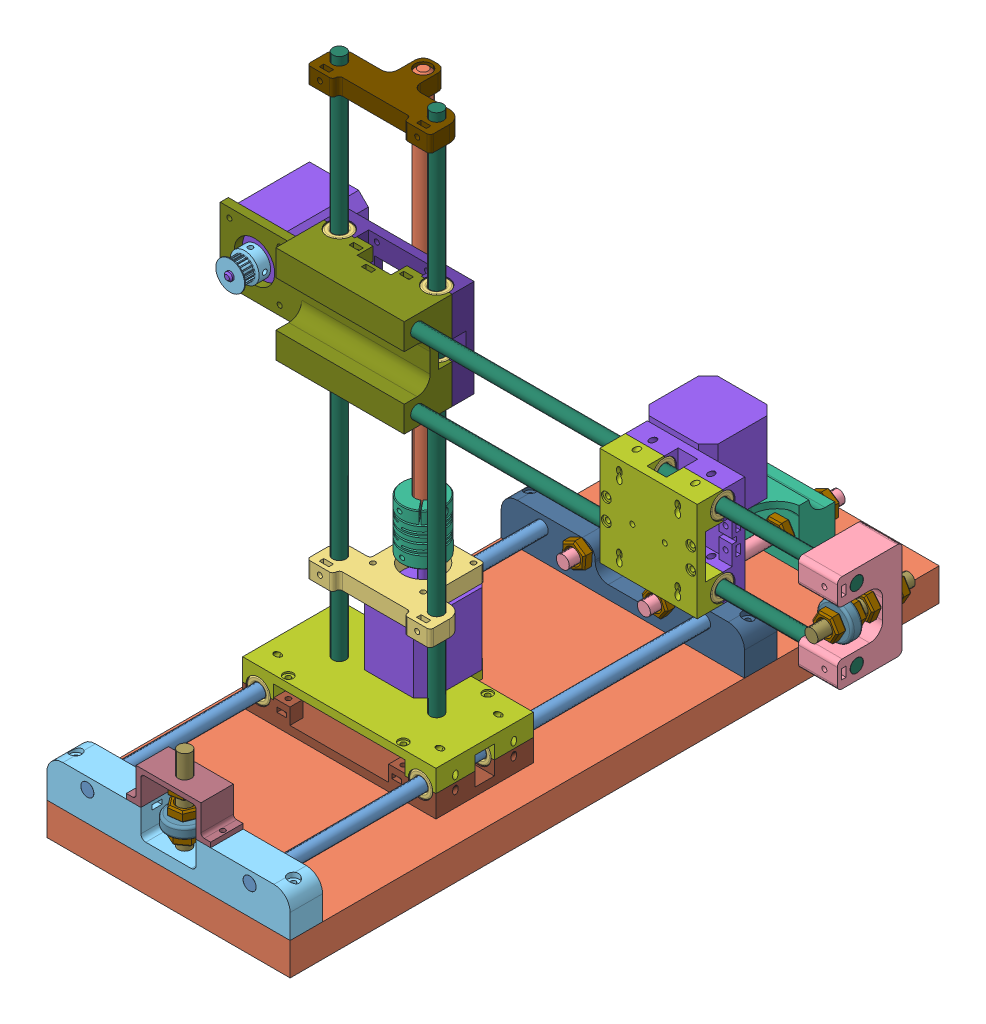
SolidWorks assembly Cartesian assembly, configuration Default. Lengths in mm.
Overall size (405.4 374.45 403.92).
61 component instances, 26 part files, 139 mates.
Components (placement in the parent):
- 8x300mm round stock-1: 8x300mm round stock [Default] at (139.3217 164.8041 244.399) size (8 8 300)
- 8x300mm round stock-2: 8x300mm round stock [Default] at (39.3217 164.8041 244.399) size (8 8 300)
- Wooden base-1: Wooden base [Default] at (89.3217 126.8041 344.399) size (150 20 400)
- LM8uu-1: LM8uu [Default] at (139.3217 164.8041 439.115) x (0.366994 -0.930223 0) z (0.930223 0.366994 0) size (15 24 15)
- LM8uu-2: LM8uu [Default] at (139.3217 164.8041 403.115) x (0.340465 -0.940257 0) z (0.940257 0.340465 0) size (15 24 15)
- LM8uu-3: LM8uu [Default] at (39.3217 164.8041 403.115) x (0.999761 -0.021839 0) z (0.021839 0.999761 0) size (15 24 15)
- LM8uu-4: LM8uu [Default] at (39.3217 164.8041 439.115) x (0.974096 0.226136 0) z (-0.226136 0.974096 0) size (15 24 15)
- 8mm threaded rod-1: 8mm threaded rod [Default] at (114.3217 164.8041 276.399) x (1 0 0) z (0 1 0) size (8 120 8)
- 8mm threaded rod-2: 8mm threaded rod [Default] at (64.3217 164.8041 156.399) x (1 0 0) z (0 -1 0) size (8 120 8)
- Base screw bracket with idler-5: Base screw bracket with idler [Default] at (89.3217 159.3041 524.399) x (1 0 0) z (0 -1 0) size (150 20 25)
- Stepper mount-1: Stepper mount [Default] at (89.0007 181.8041 211.549) x (1 0 0) z (0 0 -1) size (71.23 35 64.3)
- Main carriage-1: Main carriage [Default] at (89.3217 178.3541 409.115) x (1 0 0) z (0 0 -1) size (119.1 13.55 73.05)
- Nema 17 48mm-1: Nema 17 48mm [Default] at (89.0007 225.8041 211.549) x (-1 0 0) z (0 0 1) size (42.3 66 42.3)
- 8mm nut-1: 8mm nut [Default] at (114.3217 164.8041 162.399) x (1 0 0) z (0 -1 0) size (14.4 6 16.14)
- 8mm nut-2: 8mm nut [Default] at (114.3217 164.8041 264.399) x (0.844183 -0.536054 0) z (-0.536054 -0.844183 0) size (14.4 6 16.14)
- 8mm nut-3: 8mm nut [Default] at (64.3217 164.8041 168.399) x (0.023312 -0.999728 0) z (0.999728 0.023312 0) size (14.4 6 16.14)
- 8mm nut-4: 8mm nut [Default] at (64.3217 164.8041 270.399) x (0.389435 -0.921054 0) z (0.921054 0.389435 0) size (14.4 6 16.14)
- 8mm nut-5: 8mm nut [Default] at (114.3217 164.8041 190.399) x (0.898687 -0.438591 0) z (-0.438591 -0.898687 0) size (14.4 6 16.14)
- 8mm nut-6: 8mm nut [Default] at (114.3217 164.8041 238.399) x (0.371735 -0.928339 0) z (-0.928339 -0.371735 0) size (14.4 6 16.14)
- 8mm nut-7: 8mm nut [Default] at (64.3217 164.8041 196.399) x (1 0 0) z (0 1 0) size (14.4 6 16.14)
- 8mm nut-8: 8mm nut [Default] at (64.3217 164.8041 244.399) x (0.8519 -0.523705 0) z (0.523705 0.8519 0) size (14.4 6 16.14)
- Base screw bracket with out idler-1: Base screw bracket with out idler [Default] at (89.3217 159.3041 244.399) x (1 0 0) z (0 -1 0) size (150 20 25)
- Main carriage with set screw-1: Main carriage with set screw [Default] at (89.3217 151.2541 409.115) size (119.1 14.8 60)
- 8mm threaded rod for idler-1: 8mm threaded rod for idler [Default] at (89.3217 146.8041 534.399) x (0.152757 0 0.988264) z (-0.988264 0 0.152757) size (8 60 8)
- Idler bracket-1: Idler bracket [Default] at (89.3217 180.6682 524.399) size (52 21 20)
- 8mm ball bearing-1: 8mm ball bearing [Default] at (89.3217 168.8541 534.399) x (0.948507 0 0.316755) z (-0.316755 0 0.948507) size (22 7 22)
- 8mmx350mm-1: 8mmx350mm [Default] at (59.3217 151.2541 409.115) x (0 1 0) z (0.685543 0 0.728032) size (350 8 8)
- 8mmx350mm-2: 8mmx350mm [Default] at (119.3217 151.2541 409.115) x (0 1 0) z (0.348511 0 -0.937305) size (350 8 8)
- LM8uu-5: LM8uu [Default] at (119.3217 370.4443 409.115) x (0.524592 0 0.851354) z (0.851354 0 -0.524592) size (15 24 15)
- LM8uu-6: LM8uu [Default] at (59.3217 406.4443 409.115) x (0.379199 0 0.925315) z (0.925315 0 -0.379199) size (15 24 15)
- LM8uu-7: LM8uu [Default] at (119.3217 406.4443 409.115) x (0.235232 0 0.971939) z (0.971939 0 -0.235232) size (15 24 15)
- LM8uu-8: LM8uu [Default] at (59.3217 370.4443 409.115) x (-0.852729 0 -0.522354) z (-0.522354 0 0.852729) size (15 24 15)
- z carriage with set screw-1: z carriage with set screw [Default] at (89.3217 376.4443 422.665) x (1 0 0) z (0 1 0) size (129.4 30.8 60)
- z carriage-2: z carriage [Default] at (89.3217 376.4443 395.565) x (-1 0 0) z (0 1 0) size (79.1 31.2 60)
- 8mmx350mm-3: 8mmx350mm [Default] at (49.7717 398.4443 430.665) x (1 0 0) z (0 -0.803458 -0.595361) size (350 8 8)
- 8mmx350mm-4: 8mmx350mm [Default] at (49.7717 354.4443 430.665) x (1 0 0) z (0 -0.831172 -0.556016) size (350 8 8)
- Top spacer-1: Top spacer [Default] at (89.3217 486.2541 409.115) x (1 0 0) z (0 0 1) size (76 10 40.7)
- Lift nut-1: Lift nut [Default] at (89.3217 364.8673 387.412) x (0.5 0 -0.866025) z (0.866025 0 0.5) size (30 25.25 30)
- Lift rod-1: Lift rod [Default] at (89.3217 246.3541 387.412) x (-0.592349 0 0.805681) z (-0.805681 0 -0.592349) size (10 250 10)
- Nema 17 48mm-2: Nema 17 48mm [Default] at (89.3217 178.3541 387.412) size (42.3 66 42.3)
- Stepper brace-1: Stepper brace [Default] at (89.3217 222.3541 409.115) x (1 0 0) z (0 0 1) size (76 10 52.7)
- Nema 17 48mm-3: Nema 17 48mm [Default] at (20.6217 376.4443 373.665) x (1 0 0) z (0 -1 0) size (42.3 66 42.3)
- X belt idler-1: X belt idler [Default] at (375.7717 376.4443 430.665) x (0 -1 0) z (0 0 1) size (60 24 40)
- 8mm ball bearing-2: 8mm ball bearing [Default] at (391.7717 376.4443 433.165) x (0.976827 -0.214031 0) z (-0.214031 -0.976827 0) size (22 7 22)
- 8mm threaded rod for idler-2: 8mm threaded rod for idler [Default] at (391.7717 376.4443 390.665) x (0.112676 -0.993632 0) z (-0.993632 -0.112676 0) size (8 60 8)
- 8mm nut-9: 8mm nut [Default] at (391.7717 376.4443 396.665) x (0.894515 -0.447039 0) z (-0.447039 -0.894515 0) size (14.4 6 16.14)
- 8mm nut-10: 8mm nut [Default] at (391.7717 376.4443 423.665) x (0.798629 0.601824 0) z (0.601824 -0.798629 0) size (14.4 6 16.14)
- 8mm nut-11: 8mm nut [Default] at (391.7717 376.4443 436.665) x (0.898687 -0.438591 0) z (-0.438591 -0.898687 0) size (14.4 6 16.14)
- 8mm nut-12: 8mm nut [Default] at (391.7717 376.4443 414.665) x (0.749973 0.661469 0) z (0.661469 -0.749973 0) size (14.4 6 16.14)
- GT2-Pulley-20-Teeth-5mm-Bore-1: GT2-Pulley-20-Teeth-5mm-Bore [Default] at (20.6217 376.4443 421.665) size (17.8 17.8 16)
- GT2-Pulley-20-Teeth-5mm-Bore-2: GT2-Pulley-20-Teeth-5mm-Bore [Default] at (89.0007 179.8041 211.549) x (0.98894 0 -0.148316) z (0 -1 0) size (17.8 17.8 16)
- 8mm nut-13: 8mm nut [Default] at (89.3217 189.8041 534.399) x (0.78051 0 -0.625144) z (-0.625144 0 -0.78051) size (14.4 6 16.14)
- 8mm nut-14: 8mm nut [Default] at (89.3217 165.3541 534.399) x (0.998165 0 -0.060557) z (-0.060557 0 -0.998165) size (14.4 6 16.14)
- 8mm nut-15: 8mm nut [Default] at (89.3217 178.3541 534.399) x (0.822996 0 -0.568047) z (-0.568047 0 -0.822996) size (14.4 6 16.14)
- SRB-26C-6,35-10-1: SRB-26C-6,35-10 [По умолчанию] at (89.3217 253.6541 387.412) x (0.780592 0 -0.625041) z (0 1 0) size (26.2 26.2 31.4)
- LM8uu-9: LM8uu [Default] at (281.1911 398.4443 430.665) x (0 0.86871 -0.495321) z (0 0.495321 0.86871) size (15 24 15)
- LM8uu-10: LM8uu [Default] at (317.1911 398.4443 430.665) x (0 0.486453 -0.873707) z (0 0.873707 0.486453) size (15 24 15)
- LM8uu-11: LM8uu [Default] at (281.1911 354.4443 430.665) x (0 0.81715 -0.576426) z (0 0.576426 0.81715) size (15 24 15)
- LM8uu-12: LM8uu [Default] at (317.1911 354.4443 430.665) x (0 0.462218 0.886767) z (0 -0.886767 0.462218) size (15 24 15)
- x carriage-1: x carriage [Default] at (287.1911 376.4443 446.415) x (0 -1 0) z (1 0 0) size (61.1 15.75 60)
- x carriage with nut holders-1: x carriage with nut holders [Default] at (287.1911 376.4443 417.115) x (0 1 0) z (1 0 0) size (61.1 13.55 60)
Mates (geometry in assembly coordinates):
- Coincident1: coincident aligned: plane of 8x300mm round stock-1 through (139.3217 164.8041 544.399) normal (0 0 1); plane of 8x300mm round stock-2 through (39.3217 164.8041 544.399) normal (0 0 1)
- Concentric1: concentric anti-aligned: cylinder of 8x300mm round stock-2 through (39.3217 164.8041 544.399) axis (0 0 -1) radius 4; cylinder of LM8uu-3 through (39.3217 164.8041 379.115) axis (0 0 1) radius 4
- Concentric2: concentric anti-aligned: cylinder of 8x300mm round stock-2 through (39.3217 164.8041 544.399) axis (0 0 -1) radius 4; cylinder of LM8uu-4 through (39.3217 164.8041 415.115) axis (0 0 1) radius 4
- Concentric3: concentric anti-aligned: cylinder of 8x300mm round stock-1 through (139.3217 164.8041 544.399) axis (0 0 -1) radius 4; cylinder of LM8uu-1 through (139.3217 164.8041 415.115) axis (0 0 1) radius 4
- Concentric5: concentric anti-aligned: cylinder of 8x300mm round stock-1 through (139.3217 164.8041 544.399) axis (0 0 -1) radius 4; cylinder of LM8uu-2 through (139.3217 164.8041 379.115) axis (0 0 1) radius 4
- Coincident2: coincident aligned: plane of 8x300mm round stock-1 through (139.3217 164.8041 544.399) normal (0 0 1); plane of Wooden base-1 through (14.3217 146.8041 544.399) normal (0 0 1)
- Coincident3: coincident aligned: plane of LM8uu-1 through (139.3217 164.8041 439.115) normal (0 0 1); plane of LM8uu-4 through (39.3217 164.8041 439.115) normal (0 0 1)
- Coincident4: coincident aligned: plane of LM8uu-2 through (139.3217 164.8041 403.115) normal (0 0 1); plane of LM8uu-3 through (39.3217 164.8041 403.115) normal (0 0 1)
- Coincident5: coincident aligned: plane of 8x300mm round stock-1 through (139.3217 164.8041 244.399) normal (0 1 0); plane of 8x300mm round stock-2 through (39.3217 164.8041 244.399) normal (0 1 0)
- Coincident12: coincident anti-aligned: plane of 8mm threaded rod-1 through (114.3217 164.8041 276.399) normal (0 1 0); plane of 8mm threaded rod-2 through (64.3217 164.8041 156.399) normal (0 -1 0)
- Coincident13: coincident aligned: plane of 8x300mm round stock-1 through (139.3217 164.8041 244.399) normal (0 1 0); plane of 8mm threaded rod-1 through (114.3217 164.8041 276.399) normal (0 1 0)
- Concentric6: concentric aligned: cylinder of 8x300mm round stock-1 through (139.3217 164.8041 544.399) axis (0 0 -1) radius 4; cylinder of Base screw bracket with idler-5 through (139.3217 164.8041 544.399) axis (0 0 -1) radius 4.05
- Concentric12: concentric aligned: cylinder of 8x300mm round stock-2 through (39.3217 164.8041 544.399) axis (0 0 -1) radius 4; cylinder of Base screw bracket with idler-5 through (39.3217 164.8041 544.399) axis (0 0 -1) radius 4.05
- Coincident18: coincident aligned: plane of Wooden base-1 through (14.3217 146.8041 544.399) normal (0 0 1); plane of Base screw bracket with idler-5 through (89.3217 159.3041 544.399) normal (0 0 1)
- Coincident19: coincident anti-aligned: plane of Wooden base-1 through (89.3217 146.8041 344.399) normal (0 1 0); plane of Base screw bracket with idler-5 through (14.3217 146.8041 544.399) normal (0 -1 0)
- Coincident20: coincident aligned: plane of Wooden base-1 through (164.3217 146.8041 144.399) normal (1 0 0); plane of Base screw bracket with idler-5 through (164.3217 171.8041 544.399) normal (1 0 0)
- Coincident22: coincident anti-aligned: plane of Wooden base-1 through (89.3217 146.8041 344.399) normal (0 1 0); plane of Stepper mount-1 through (89.0007 146.8041 184.399) normal (0 -1 0)
- Concentric14: concentric anti-aligned: cylinder of 8mm threaded rod-2 through (64.3217 164.8041 276.399) axis (0 0 -1) radius 4; cylinder of Stepper mount-1 through (64.3217 164.8041 168.399) axis (0 0 1) radius 4.05
- Concentric15: concentric anti-aligned: cylinder of LM8uu-2 through (139.3217 164.8041 379.115) axis (0 0 1) radius 7.5; cylinder of Main carriage-1 through (139.3217 164.8041 403.115) axis (0 0 -1) radius 7.55
- Concentric16: concentric aligned: cylinder of LM8uu-4 through (39.3217 164.8041 415.115) axis (0 0 1) radius 7.5; cylinder of Main carriage-1 through (39.3217 164.8041 415.115) axis (0 0 1) radius 7.55
- Coincident23: coincident aligned: plane of LM8uu-4 through (39.3217 164.8041 439.115) normal (0 0 1); plane of Main carriage-1 through (29.7717 173.3541 439.115) normal (0 0 1)
- Coincident24: coincident aligned: plane of LM8uu-1 through (139.3217 164.8041 439.115) normal (0 0 1); plane of Main carriage-1 through (29.7717 173.3541 439.115) normal (0 0 1)
- Coincident25: coincident aligned: plane of LM8uu-2 through (139.3217 164.8041 379.115) normal (0 0 -1); plane of Main carriage-1 through (29.7717 173.3541 379.115) normal (0 0 -1)
- Coincident26: coincident aligned: plane of LM8uu-3 through (39.3217 164.8041 379.115) normal (0 0 -1); plane of Main carriage-1 through (29.7717 173.3541 379.115) normal (0 0 -1)
- Coincident27: coincident anti-aligned: plane of Stepper mount-1 through (89.0007 181.8041 211.549) normal (0 1 0); plane of Nema 17 48mm-1 through (89.0007 181.8041 211.549) normal (0 -1 0)
- Coincident28: coincident aligned: plane of Stepper mount-1 through (110.1507 177.8041 232.699) normal (1 0 0); plane of Nema 17 48mm-1 through (110.1507 181.8041 211.549) normal (1 0 0)
- Coincident29: coincident aligned: plane of Stepper mount-1 through (67.8507 177.8041 232.699) normal (0 0 1); plane of Nema 17 48mm-1 through (89.0007 181.8041 232.699) normal (0 0 1)
- Concentric21: concentric anti-aligned: cylinder of 8mm threaded rod-1 through (114.3217 164.8041 156.399) axis (0 0 1) radius 4; cylinder of 8mm nut-2 through (114.3217 164.8041 270.399) axis (0 0 -1) radius 4
- Concentric22: concentric anti-aligned: cylinder of 8mm threaded rod-2 through (64.3217 164.8041 276.399) axis (0 0 -1) radius 4; cylinder of 8mm nut-3 through (64.3217 164.8041 162.399) axis (0 0 1) radius 4
- Concentric23: concentric anti-aligned: cylinder of 8mm threaded rod-1 through (114.3217 164.8041 156.399) axis (0 0 1) radius 4; cylinder of 8mm nut-1 through (114.3217 164.8041 168.399) axis (0 0 -1) radius 4
- Concentric24: concentric anti-aligned: cylinder of 8mm threaded rod-2 through (64.3217 164.8041 276.399) axis (0 0 -1) radius 4; cylinder of 8mm nut-4 through (64.3217 164.8041 264.399) axis (0 0 1) radius 4
- Concentric25: concentric anti-aligned: cylinder of 8mm threaded rod-1 through (114.3217 164.8041 156.399) axis (0 0 1) radius 4; cylinder of 8mm nut-5 through (114.3217 164.8041 196.399) axis (0 0 -1) radius 4
- Concentric26: concentric anti-aligned: cylinder of 8mm threaded rod-1 through (114.3217 164.8041 156.399) axis (0 0 1) radius 4; cylinder of 8mm nut-6 through (114.3217 164.8041 244.399) axis (0 0 -1) radius 4
- Concentric27: concentric anti-aligned: cylinder of 8mm threaded rod-2 through (64.3217 164.8041 276.399) axis (0 0 -1) radius 4; cylinder of 8mm nut-8 through (64.3217 164.8041 238.399) axis (0 0 1) radius 4
- Concentric28: concentric anti-aligned: cylinder of 8mm threaded rod-2 through (64.3217 164.8041 276.399) axis (0 0 -1) radius 4; cylinder of 8mm nut-7 through (64.3217 164.8041 190.399) axis (0 0 1) radius 4
- Coincident35: coincident anti-aligned: plane of Stepper mount-1 through (89.0007 181.8041 168.399) normal (0 0 -1); plane of 8mm nut-3 through (64.3217 164.8041 168.399) normal (0 0 1)
- Coincident36: coincident anti-aligned: plane of Stepper mount-1 through (89.0007 181.8041 168.399) normal (0 0 -1); plane of 8mm nut-1 through (114.3217 164.8041 168.399) normal (0 0 1)
- Coincident37: coincident anti-aligned: plane of Stepper mount-1 through (89.0007 181.8041 190.399) normal (0 0 1); plane of 8mm nut-7 through (64.3217 164.8041 190.399) normal (0 0 -1)
- Coincident38: coincident anti-aligned: plane of Stepper mount-1 through (89.0007 181.8041 190.399) normal (0 0 1); plane of 8mm nut-5 through (114.3217 164.8041 190.399) normal (0 0 -1)
- Concentric33: concentric aligned: cylinder of 8x300mm round stock-2 through (39.3217 164.8041 544.399) axis (0 0 -1) radius 4; cylinder of Base screw bracket with out idler-1 through (39.3217 164.8041 264.399) axis (0 0 -1) radius 4.05
- Concentric34: concentric aligned: cylinder of 8x300mm round stock-1 through (139.3217 164.8041 544.399) axis (0 0 -1) radius 4; cylinder of Base screw bracket with out idler-1 through (139.3217 164.8041 264.399) axis (0 0 -1) radius 4.05
- Coincident43: coincident aligned: plane of 8x300mm round stock-1 through (139.3217 164.8041 244.399) normal (0 0 -1); plane of Base screw bracket with out idler-1 through (89.3217 159.3041 244.399) normal (0 0 -1)
- Coincident45: coincident anti-aligned: plane of 8mm nut-8 through (64.3217 164.8041 244.399) normal (0 0 1); plane of Base screw bracket with out idler-1 through (89.3217 159.3041 244.399) normal (0 0 -1)
- Coincident46: coincident anti-aligned: plane of 8mm nut-6 through (114.3217 164.8041 244.399) normal (0 0 1); plane of Base screw bracket with out idler-1 through (89.3217 159.3041 244.399) normal (0 0 -1)
- Coincident47: coincident anti-aligned: plane of 8mm nut-2 through (114.3217 164.8041 264.399) normal (0 0 -1); plane of Base screw bracket with out idler-1 through (89.3217 159.3041 264.399) normal (0 0 1)
- Coincident48: coincident anti-aligned: plane of 8mm nut-4 through (64.3217 164.8041 264.399) normal (0 0 -1); plane of Base screw bracket with out idler-1 through (89.3217 159.3041 264.399) normal (0 0 1)
- Distance3: distance = 12 mm aligned: plane of 8mm threaded rod-1 through (114.3217 164.8041 276.399) normal (0 0 1); plane of Base screw bracket with out idler-1 through (89.3217 159.3041 264.399) normal (0 0 1)
- Distance4: distance = 12 mm aligned: plane of 8mm threaded rod-2 through (64.3217 164.8041 276.399) normal (0 0 1); plane of Base screw bracket with out idler-1 through (89.3217 159.3041 264.399) normal (0 0 1)
- Distance5: distance = 12 mm aligned: plane of 8mm threaded rod-1 through (114.3217 164.8041 156.399) normal (0 0 -1); plane of Stepper mount-1 through (89.0007 181.8041 168.399) normal (0 0 -1)
- Concentric35: concentric anti-aligned: cylinder of LM8uu-3 through (39.3217 164.8041 379.115) axis (0 0 1) radius 7.5; cylinder of Main carriage with set screw-1 through (39.3217 164.8041 403.115) axis (0 0 -1) radius 7.55
- Concentric36: concentric aligned: cylinder of LM8uu-1 through (139.3217 164.8041 415.115) axis (0 0 1) radius 7.5; cylinder of Main carriage with set screw-1 through (139.3217 164.8041 415.115) axis (0 0 1) radius 7.55
- Coincident52: coincident aligned: plane of Main carriage-1 through (29.7717 173.3541 439.115) normal (0 0 1); plane of Main carriage with set screw-1 through (29.7717 156.2541 439.115) normal (0 0 1)
- Concentric37: concentric anti-aligned: cylinder of Base screw bracket with idler-5 through (89.3217 144.7663 534.399) axis (0 1 0) radius 4; cylinder of 8mm threaded rod for idler-1 through (89.3217 206.8041 534.399) axis (0 -1 0) radius 4
- Coincident53: coincident anti-aligned: plane of Wooden base-1 through (89.3217 146.8041 344.399) normal (0 1 0); plane of 8mm threaded rod for idler-1 through (89.3217 146.8041 534.399) normal (0 -1 0)
- Concentric38: concentric aligned: cylinder of 8mm threaded rod-2 through (64.3217 164.8041 276.399) axis (0 0 -1) radius 4; cylinder of Base screw bracket with out idler-1 through (64.3217 164.8041 264.399) axis (0 0 -1) radius 4.05
- Concentric39: concentric anti-aligned: cylinder of 8mm threaded rod-1 through (114.3217 164.8041 156.399) axis (0 0 1) radius 4; cylinder of Base screw bracket with out idler-1 through (114.3217 164.8041 264.399) axis (0 0 -1) radius 4.05
- Coincident54: coincident anti-aligned: plane of Base screw bracket with idler-5 through (14.3217 171.8041 544.399) normal (0 1 0); plane of Idler bracket-1 through (72.3217 171.8041 544.399) normal (0 -1 0)
- Coincident55: coincident aligned: plane of Base screw bracket with idler-5 through (89.3217 159.3041 544.399) normal (0 0 1); plane of Idler bracket-1 through (89.3217 180.6682 544.399) normal (0 0 1)
- Concentric40: concentric anti-aligned: cylinder of 8mm threaded rod for idler-1 through (89.3217 206.8041 534.399) axis (0 -1 0) radius 4; cylinder of Idler bracket-1 through (89.3217 176.8041 534.399) axis (0 1 0) radius 4.05
- Concentric41: concentric aligned: cylinder of 8mm threaded rod for idler-1 through (89.3217 206.8041 534.399) axis (0 -1 0) radius 4; cylinder of 8mm ball bearing-1 through (89.3217 172.3541 534.399) axis (0 -1 0) radius 4
- Concentric42: concentric anti-aligned: cylinder of Main carriage-1 through (59.3217 164.9541 409.115) axis (0 1 0) radius 4; cylinder of 8mmx350mm-1 through (59.3217 501.2541 409.115) axis (0 -1 0) radius 4
- Concentric43: concentric anti-aligned: cylinder of Main carriage-1 through (119.3217 164.9541 409.115) axis (0 1 0) radius 4; cylinder of 8mmx350mm-2 through (119.3217 501.2541 409.115) axis (0 -1 0) radius 4
- Coincident56: coincident aligned: plane of Main carriage with set screw-1 through (89.3217 151.2541 409.115) normal (0 -1 0); plane of 8mmx350mm-2 through (119.3217 151.2541 409.115) normal (0 -1 0)
- Coincident57: coincident aligned: plane of Main carriage with set screw-1 through (89.3217 151.2541 409.115) normal (0 -1 0); plane of 8mmx350mm-1 through (59.3217 151.2541 409.115) normal (0 -1 0)
- Concentric49: concentric anti-aligned: cylinder of 8mmx350mm-1 through (59.3217 501.2541 409.115) axis (0 -1 0) radius 4; cylinder of LM8uu-8 through (59.3217 346.4443 409.115) axis (0 1 0) radius 4
- Concentric50: concentric anti-aligned: cylinder of 8mmx350mm-2 through (119.3217 501.2541 409.115) axis (0 -1 0) radius 4; cylinder of LM8uu-7 through (119.3217 382.4443 409.115) axis (0 1 0) radius 4
- Concentric52: concentric anti-aligned: cylinder of LM8uu-6 through (59.3217 382.4443 409.115) axis (0 1 0) radius 7.5; cylinder of z carriage-2 through (59.3217 370.4443 409.115) axis (0 -1 0) radius 7.55
- Concentric54: concentric anti-aligned: cylinder of 8mmx350mm-1 through (59.3217 501.2541 409.115) axis (0 -1 0) radius 4; cylinder of LM8uu-6 through (59.3217 382.4443 409.115) axis (0 1 0) radius 4
- Concentric55: concentric anti-aligned: cylinder of 8mmx350mm-2 through (119.3217 501.2541 409.115) axis (0 -1 0) radius 4; cylinder of LM8uu-5 through (119.3217 346.4443 409.115) axis (0 1 0) radius 4
- Concentric57: concentric aligned: cylinder of LM8uu-7 through (119.3217 382.4443 409.115) axis (0 1 0) radius 7.5; cylinder of z carriage-2 through (119.3217 382.4443 409.115) axis (0 1 0) radius 7.55
- Concentric58: concentric aligned: cylinder of LM8uu-7 through (119.3217 382.4443 409.115) axis (0 1 0) radius 7.5; cylinder of z carriage with set screw-1 through (119.3217 382.4443 409.115) axis (0 1 0) radius 7.55
- Concentric59: concentric anti-aligned: cylinder of LM8uu-6 through (59.3217 382.4443 409.115) axis (0 1 0) radius 7.5; cylinder of z carriage with set screw-1 through (59.3217 370.4443 409.115) axis (0 -1 0) radius 7.55
- Coincident62: coincident aligned: plane of LM8uu-7 through (119.3217 406.4443 409.115) normal (0 1 0); plane of z carriage-2 through (128.8717 406.4443 400.565) normal (0 1 0)
- Coincident63: coincident aligned: plane of LM8uu-5 through (119.3217 346.4443 409.115) normal (0 -1 0); plane of z carriage with set screw-1 through (49.7717 346.4443 417.665) normal (0 -1 0)
- Coincident64: coincident aligned: plane of z carriage with set screw-1 through (49.7717 406.4443 417.665) normal (0 1 0); plane of z carriage-2 through (128.8717 406.4443 400.565) normal (0 1 0)
- Coincident65: coincident aligned: plane of LM8uu-6 through (59.3217 406.4443 409.115) normal (0 1 0); plane of z carriage with set screw-1 through (49.7717 406.4443 417.665) normal (0 1 0)
- Coincident66: coincident aligned: plane of LM8uu-8 through (59.3217 346.4443 409.115) normal (0 -1 0); plane of z carriage with set screw-1 through (49.7717 346.4443 417.665) normal (0 -1 0)
- Concentric60: concentric anti-aligned: cylinder of z carriage with set screw-1 through (49.7717 398.4443 430.665) axis (1 0 0) radius 4.05; cylinder of 8mmx350mm-3 through (399.7717 398.4443 430.665) axis (-1 0 0) radius 4
- Concentric61: concentric anti-aligned: cylinder of z carriage with set screw-1 through (49.7717 354.4443 430.665) axis (1 0 0) radius 4.05; cylinder of 8mmx350mm-4 through (399.7717 354.4443 430.665) axis (-1 0 0) radius 4
- Coincident67: coincident aligned: plane of 8mmx350mm-3 through (399.7717 398.4443 430.665) normal (1 0 0); plane of 8mmx350mm-4 through (399.7717 354.4443 430.665) normal (1 0 0)
- Concentric62: concentric aligned: cylinder of 8mmx350mm-1 through (59.3217 501.2541 409.115) axis (0 -1 0) radius 4; cylinder of Top spacer-1 through (59.3217 496.2541 409.115) axis (0 -1 0) radius 4.125
- Concentric63: concentric aligned: cylinder of 8mmx350mm-2 through (119.3217 501.2541 409.115) axis (0 -1 0) radius 4; cylinder of Top spacer-1 through (119.3217 496.2541 409.115) axis (0 -1 0) radius 4.125
- Distance18: distance = 5 mm aligned: plane of 8mmx350mm-2 through (119.3217 501.2541 409.115) normal (0 1 0); plane of Top spacer-1 through (89.3217 496.2541 409.115) normal (0 1 0)
- Coincident69: coincident aligned: plane of z carriage with set screw-1 through (49.7717 346.4443 417.665) normal (-1 0 0); plane of 8mmx350mm-3 through (49.7717 398.4443 430.665) normal (-1 0 0)
- Concentric64: concentric aligned: cylinder of z carriage-2 through (89.3217 356.4443 387.412) axis (0 1 0) radius 8.15; cylinder of Lift nut-1 through (89.3217 370.8673 387.412) axis (0 1 0) radius 8
- Coincident72: coincident anti-aligned: plane of z carriage-2 through (89.3217 366.4443 395.565) normal (0 1 0); plane of Lift nut-1 through (85.3217 366.4443 394.3402) normal (0 -1 0)
- Concentric65: concentric aligned: cylinder of z carriage-2 through (99.714 356.4443 381.412) axis (0 1 0) radius 1.5; cylinder of Lift nut-1 through (99.714 361.6943 381.412) axis (0 1 0) radius 1.5
- Concentric66: concentric anti-aligned: cylinder of Lift nut-1 through (89.3217 370.8673 387.412) axis (0 1 0) radius 5; cylinder of Lift rod-1 through (89.3217 496.3541 387.412) axis (0 -1 0) radius 5
- Coincident73: coincident anti-aligned: plane of Main carriage-1 through (89.3217 178.3541 409.115) normal (0 1 0); plane of Nema 17 48mm-2 through (89.3217 178.3541 387.412) normal (0 -1 0)
- Concentric67: concentric aligned: cylinder of Lift rod-1 through (89.3217 496.3541 387.412) axis (0 -1 0) radius 5; cylinder of Nema 17 48mm-2 through (89.3217 244.3541 387.412) axis (0 -1 0) radius 2.5
- Parallel1: parallel aligned: plane of Main carriage-1 through (68.1717 129.0868 366.065) normal (0 0 -1); plane of Nema 17 48mm-2 through (89.3217 222.3541 366.262) normal (0 0 -1)
- Concentric68: concentric aligned: cylinder of 8mmx350mm-2 through (119.3217 501.2541 409.115) axis (0 -1 0) radius 4; cylinder of Stepper brace-1 through (119.3217 232.3541 409.115) axis (0 -1 0) radius 4.125
- Concentric69: concentric aligned: cylinder of 8mmx350mm-1 through (59.3217 501.2541 409.115) axis (0 -1 0) radius 4; cylinder of Stepper brace-1 through (59.3217 232.3541 409.115) axis (0 -1 0) radius 4.125
- Coincident74: coincident anti-aligned: plane of Nema 17 48mm-2 through (89.3217 222.3541 387.412) normal (0 1 0); plane of Stepper brace-1 through (89.3217 222.3541 409.115) normal (0 -1 0)
- Coincident78: coincident anti-aligned: plane of z carriage with set screw-1 through (89.3217 376.4443 417.665) normal (0 0 -1); plane of Nema 17 48mm-3 through (20.6217 376.4443 417.665) normal (0 0 1)
- Coincident79: coincident aligned: plane of z carriage with set screw-1 through (-0.5283 376.4443 417.665) normal (-1 0 0); plane of Nema 17 48mm-3 through (-0.5283 376.4443 417.665) normal (-1 0 0)
- Coincident80: coincident aligned: plane of z carriage with set screw-1 through (89.3217 397.5943 417.665) normal (0 1 0); plane of Nema 17 48mm-3 through (20.6217 397.5943 417.665) normal (0 1 0)
- Concentric71: concentric aligned: cylinder of 8mmx350mm-3 through (399.7717 398.4443 430.665) axis (-1 0 0) radius 4; cylinder of X belt idler-1 through (399.7717 398.4443 430.665) axis (-1 0 0) radius 4.125
- Concentric72: concentric aligned: cylinder of 8mmx350mm-4 through (399.7717 354.4443 430.665) axis (-1 0 0) radius 4; cylinder of X belt idler-1 through (399.7717 354.4443 430.665) axis (-1 0 0) radius 4.125
- Coincident81: coincident aligned: plane of 8mmx350mm-3 through (399.7717 398.4443 430.665) normal (1 0 0); plane of X belt idler-1 through (399.7717 376.4443 430.665) normal (1 0 0)
- Concentric73: concentric anti-aligned: cylinder of X belt idler-1 through (391.7717 376.4443 402.665) axis (0 0 1) radius 4; cylinder of 8mm ball bearing-2 through (391.7717 376.4443 436.665) axis (0 0 -1) radius 4
- Concentric74: concentric anti-aligned: cylinder of X belt idler-1 through (391.7717 376.4443 402.665) axis (0 0 1) radius 4; cylinder of 8mm threaded rod for idler-2 through (391.7717 376.4443 450.665) axis (0 0 -1) radius 4
- Distance11: distance = 12 mm aligned: plane of 8mm threaded rod for idler-2 through (391.7717 376.4443 390.665) normal (0 0 -1); plane of X belt idler-1 through (399.7717 376.4443 402.665) normal (0 0 -1)
- Concentric75: concentric aligned: cylinder of 8mm threaded rod for idler-2 through (391.7717 376.4443 450.665) axis (0 0 -1) radius 4; cylinder of 8mm nut-9 through (391.7717 376.4443 402.665) axis (0 0 -1) radius 4
- Concentric76: concentric aligned: cylinder of 8mm threaded rod for idler-2 through (391.7717 376.4443 450.665) axis (0 0 -1) radius 4; cylinder of 8mm nut-11 through (391.7717 376.4443 442.665) axis (0 0 -1) radius 4
- Concentric77: concentric aligned: cylinder of 8mm threaded rod for idler-2 through (391.7717 376.4443 450.665) axis (0 0 -1) radius 4; cylinder of 8mm nut-10 through (391.7717 376.4443 429.665) axis (0 0 -1) radius 4
- Coincident83: coincident anti-aligned: plane of X belt idler-1 through (399.7717 376.4443 402.665) normal (0 0 -1); plane of 8mm nut-9 through (391.7717 376.4443 402.665) normal (0 0 1)
- Coincident84: coincident anti-aligned: plane of 8mm ball bearing-2 through (391.7717 376.4443 436.665) normal (0 0 1); plane of 8mm nut-11 through (391.7717 376.4443 436.665) normal (0 0 -1)
- Concentric78: concentric aligned: cylinder of 8mm threaded rod for idler-2 through (391.7717 376.4443 450.665) axis (0 0 -1) radius 4; cylinder of 8mm nut-12 through (391.7717 376.4443 420.665) axis (0 0 -1) radius 4
- Coincident86: coincident anti-aligned: plane of X belt idler-1 through (399.7717 376.4443 414.665) normal (0 0 1); plane of 8mm nut-12 through (391.7717 376.4443 414.665) normal (0 0 -1)
- Coincident87: coincident anti-aligned: plane of 8mm ball bearing-2 through (391.7717 376.4443 429.665) normal (0 0 -1); plane of 8mm nut-10 through (391.7717 376.4443 429.665) normal (0 0 1)
- Concentric79: concentric anti-aligned: cylinder of Nema 17 48mm-3 through (20.6217 376.4443 439.665) axis (0 0 -1) radius 2.5; cylinder of GT2-Pulley-20-Teeth-5mm-Bore-1 through (20.6217 376.4443 501.2744) axis (0 0 1) radius 2.5
- Concentric80: concentric anti-aligned: cylinder of Nema 17 48mm-1 through (89.0007 159.8041 211.549) axis (0 1 0) radius 2.5; cylinder of GT2-Pulley-20-Teeth-5mm-Bore-2 through (89.0007 100.1946 211.549) axis (0 -1 0) radius 2.5
- Distance12: distance = 4 mm aligned: plane of GT2-Pulley-20-Teeth-5mm-Bore-2 through (90.3208 163.8041 220.3506) normal (0 -1 0); plane of Nema 17 48mm-1 through (89.0007 159.8041 211.549) normal (0 -1 0)
- Distance13: distance = 2 mm aligned: plane of GT2-Pulley-20-Teeth-5mm-Bore-1 through (20.6217 385.3443 437.665) normal (0 0 1); plane of Nema 17 48mm-3 through (20.6217 376.4443 439.665) normal (0 0 1)
- Distance14: distance = 15 mm anti-aligned: plane of 8mm ball bearing-2 through (391.7717 376.4443 429.665) normal (0 0 -1); plane of X belt idler-1 through (399.7717 376.4443 414.665) normal (0 0 1)
- Coincident91: coincident aligned: plane of Main carriage-1 through (89.3217 165.3541 409.115) normal (0 -1 0); plane of 8mm ball bearing-1 through (89.3217 165.3541 534.399) normal (0 -1 0)
- Concentric81: concentric anti-aligned: cylinder of 8mm threaded rod for idler-1 through (89.3217 206.8041 534.399) axis (0 -1 0) radius 4; cylinder of 8mm nut-15 through (89.3217 172.3541 534.399) axis (0 1 0) radius 4
- Concentric82: concentric anti-aligned: cylinder of 8mm threaded rod for idler-1 through (89.3217 206.8041 534.399) axis (0 -1 0) radius 4; cylinder of 8mm nut-14 through (89.3217 159.3541 534.399) axis (0 1 0) radius 4
- Concentric83: concentric anti-aligned: cylinder of 8mm threaded rod for idler-1 through (89.3217 206.8041 534.399) axis (0 -1 0) radius 4; cylinder of 8mm nut-13 through (89.3217 183.8041 534.399) axis (0 1 0) radius 4
- Coincident94: coincident anti-aligned: plane of Idler bracket-1 through (106.3217 189.8041 544.399) normal (0 -1 0); plane of 8mm nut-13 through (89.3217 189.8041 534.399) normal (0 1 0)
- Coincident95: coincident anti-aligned: plane of 8mm ball bearing-1 through (89.3217 165.3541 534.399) normal (0 -1 0); plane of 8mm nut-14 through (89.3217 165.3541 534.399) normal (0 1 0)
- Coincident96: coincident anti-aligned: plane of 8mm ball bearing-1 through (89.3217 172.3541 534.399) normal (0 1 0); plane of 8mm nut-15 through (89.3217 172.3541 534.399) normal (0 -1 0)
- Concentric84: concentric aligned: cylinder of Nema 17 48mm-2 through (89.3217 244.3541 387.412) axis (0 -1 0) radius 2.5; cylinder of SRB-26C-6,35-10-1 through (89.3217 255.3343 387.412) axis (0 -1 0) radius 3.175
- Distance15: distance = 1 mm aligned: plane of SRB-26C-6,35-10-1 through (86.0015 245.3541 406.8527) normal (0 1 0); plane of Nema 17 48mm-2 through (89.3217 244.3541 387.412) normal (0 1 0)
- Distance16: distance = 1 mm anti-aligned: plane of Lift rod-1 through (89.3217 246.3541 387.412) normal (0 -1 0); plane of SRB-26C-6,35-10-1 through (86.0015 245.3541 406.8527) normal (0 1 0)
- Concentric85: concentric anti-aligned: cylinder of 8mmx350mm-3 through (399.7717 398.4443 430.665) axis (-1 0 0) radius 4; cylinder of LM8uu-9 through (257.1911 398.4443 430.665) axis (1 0 0) radius 4
- Concentric86: concentric anti-aligned: cylinder of 8mmx350mm-3 through (399.7717 398.4443 430.665) axis (-1 0 0) radius 4; cylinder of LM8uu-10 through (293.1911 398.4443 430.665) axis (1 0 0) radius 4
- Concentric87: concentric anti-aligned: cylinder of 8mmx350mm-4 through (399.7717 354.4443 430.665) axis (-1 0 0) radius 4; cylinder of LM8uu-11 through (257.1911 354.4443 430.665) axis (1 0 0) radius 4
- Concentric88: concentric anti-aligned: cylinder of 8mmx350mm-4 through (399.7717 354.4443 430.665) axis (-1 0 0) radius 4; cylinder of LM8uu-12 through (293.1911 354.4443 430.665) axis (1 0 0) radius 4
- Coincident97: coincident aligned: plane of LM8uu-10 through (317.1911 398.4443 430.665) normal (1 0 0); plane of LM8uu-12 through (317.1911 354.4443 430.665) normal (1 0 0)
- Coincident98: coincident aligned: plane of LM8uu-9 through (257.1911 398.4443 430.665) normal (-1 0 0); plane of LM8uu-11 through (257.1911 354.4443 430.665) normal (-1 0 0)
- Concentric90: concentric anti-aligned: cylinder of LM8uu-10 through (293.1911 398.4443 430.665) axis (1 0 0) radius 7.5; cylinder of x carriage-1 through (281.1911 398.4443 430.665) axis (-1 0 0) radius 7.55
- Concentric91: concentric aligned: cylinder of LM8uu-12 through (293.1911 354.4443 430.665) axis (1 0 0) radius 7.5; cylinder of x carriage-1 through (293.1911 354.4443 430.665) axis (1 0 0) radius 7.55
- Concentric93: concentric aligned: cylinder of LM8uu-10 through (293.1911 398.4443 430.665) axis (1 0 0) radius 7.5; cylinder of x carriage with nut holders-1 through (293.1911 398.4443 430.665) axis (1 0 0) radius 7.55
- Concentric94: concentric aligned: cylinder of LM8uu-12 through (293.1911 354.4443 430.665) axis (1 0 0) radius 7.5; cylinder of x carriage with nut holders-1 through (293.1911 354.4443 430.665) axis (1 0 0) radius 7.55
- Coincident99: coincident aligned: plane of x carriage-1 through (317.1911 406.9943 441.415) normal (1 0 0); plane of x carriage with nut holders-1 through (317.1911 345.8943 422.115) normal (1 0 0)
- Coincident100: coincident aligned: plane of LM8uu-10 through (317.1911 398.4443 430.665) normal (1 0 0); plane of x carriage-1 through (317.1911 406.9943 441.415) normal (1 0 0)
- Coincident101: coincident aligned: plane of LM8uu-9 through (257.1911 398.4443 430.665) normal (-1 0 0); plane of x carriage-1 through (257.1911 406.9943 441.415) normal (-1 0 0)
